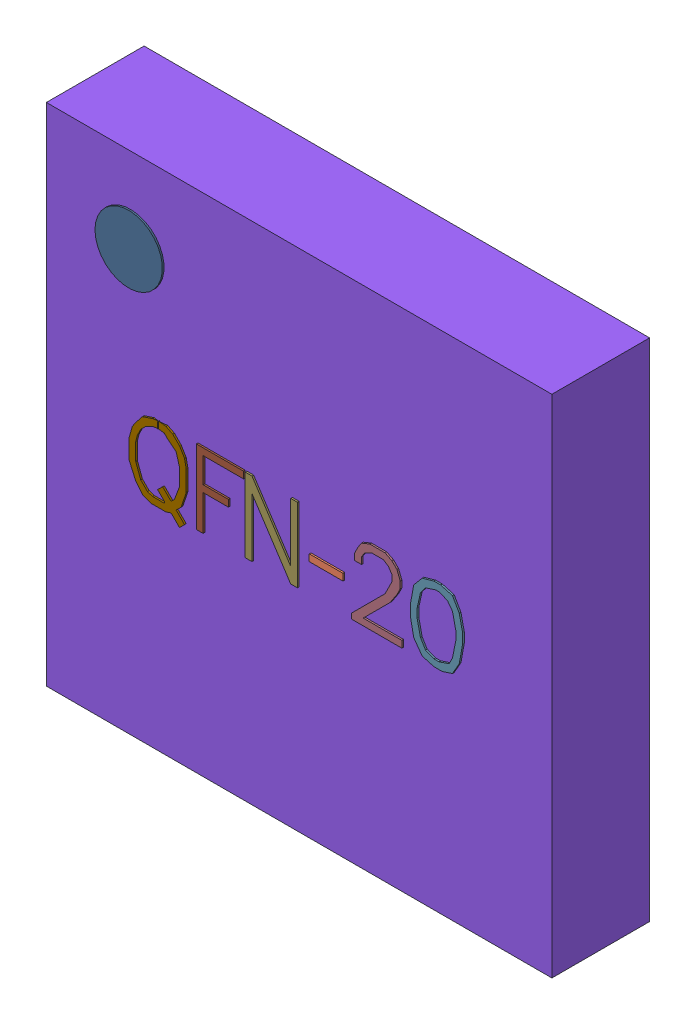
SolidWorks assembly User Library-QFN-20, configuration Default. Lengths in mm.
Overall size (3 3 0.73).
60 component instances, 15 part files, 0 mates.
Components (placement in the parent):
- User Library-QFN-20_Free-Models1-1: User Library-QFN-20_Free-Models1 [Default] at origin size (3 3 0.63)
  - User Library-QFN-20_479712337-1: User Library-QFN-20_479712337 [Default] at (0.045 -2.02 0.0127) size (0.35 0.3 0.02)
    - User Library-QFN-20_Extruded16-1: User Library-QFN-20_Extruded16 [Default] at origin size (0.35 0.3 0.02)
  - User Library-QFN-20_479712337-2: User Library-QFN-20_479712337 [Default] at (0.045 -1.52 0.0127) size (0.35 0.3 0.02)
    - User Library-QFN-20_Extruded16-1: User Library-QFN-20_Extruded16 [Default] at origin size (0.35 0.3 0.02)
  - User Library-QFN-20_479712337-3: User Library-QFN-20_479712337 [Default] at (0.045 -1.02 0.0127) size (0.35 0.3 0.02)
    - User Library-QFN-20_Extruded16-1: User Library-QFN-20_Extruded16 [Default] at origin size (0.35 0.3 0.02)
  - User Library-QFN-20_479711313-1: User Library-QFN-20_479711313 [Default] at (1.44 -1.32 0.6127) size (0.2 0.04 0.01)
    - User Library-QFN-20_Extruded23-1: User Library-QFN-20_Extruded23 [Default] at origin size (0.2 0.04 0.01)
  - User Library-QFN-20_479711441-1: User Library-QFN-20_479711441 [Default] at (0.005 -0.005 0.0127) size (0.43 0.43 0.02)
    - User Library-QFN-20_Extruded21-1: User Library-QFN-20_Extruded21 [Default] at origin size (0.43 0.43 0.02)
  - User Library-QFN-20_479711441-2: User Library-QFN-20_479711441 [Default] at (2.535 -0.005 0.0127) size (0.43 0.43 0.02)
    - User Library-QFN-20_Extruded21-1: User Library-QFN-20_Extruded21 [Default] at origin size (0.43 0.43 0.02)
  - User Library-QFN-20_479711441-3: User Library-QFN-20_479711441 [Default] at (2.535 -2.535 0.0127) size (0.43 0.43 0.02)
    - User Library-QFN-20_Extruded21-1: User Library-QFN-20_Extruded21 [Default] at origin size (0.43 0.43 0.02)
  - User Library-QFN-20_479712337-4: User Library-QFN-20_479712337 [Default] at (0.045 -0.52 0.0127) size (0.35 0.3 0.02)
    - User Library-QFN-20_Extruded16-1: User Library-QFN-20_Extruded16 [Default] at origin size (0.35 0.3 0.02)
  - User Library-QFN-20_479712209-1: User Library-QFN-20_479712209 [Default] at (2.02 -0.045 0.0127) size (0.3 0.35 0.02)
    - User Library-QFN-20_Extruded20-1: User Library-QFN-20_Extruded20 [Default] at origin size (0.3 0.35 0.02)
  - User Library-QFN-20_479706833-1: User Library-QFN-20_479706833 [Default] at (2.495 -2.02 0.0127) size (0.35 0.3 0.02)
    - User Library-QFN-20_Extruded19-1: User Library-QFN-20_Extruded19 [Default] at origin size (0.35 0.3 0.02)
  - User Library-QFN-20_479706577-1: User Library-QFN-20_479706577 [Default] at (0.52 -2.495 0.0127) size (0.3 0.35 0.02)
    - User Library-QFN-20_Extruded22-1: User Library-QFN-20_Extruded22 [Default] at origin size (0.3 0.35 0.02)
  - User Library-QFN-20_479711441-4: User Library-QFN-20_479711441 [Default] at (0.005 -2.535 0.0127) size (0.43 0.43 0.02)
    - User Library-QFN-20_Extruded21-1: User Library-QFN-20_Extruded21 [Default] at origin size (0.43 0.43 0.02)
  - User Library-QFN-20_479706577-2: User Library-QFN-20_479706577 [Default] at (2.02 -2.495 0.0127) size (0.3 0.35 0.02)
    - User Library-QFN-20_Extruded22-1: User Library-QFN-20_Extruded22 [Default] at origin size (0.3 0.35 0.02)
  - User Library-QFN-20_479706577-3: User Library-QFN-20_479706577 [Default] at (1.52 -2.495 0.0127) size (0.3 0.35 0.02)
    - User Library-QFN-20_Extruded22-1: User Library-QFN-20_Extruded22 [Default] at origin size (0.3 0.35 0.02)
  - User Library-QFN-20_479706577-4: User Library-QFN-20_479706577 [Default] at (1.02 -2.495 0.0127) size (0.3 0.35 0.02)
    - User Library-QFN-20_Extruded22-1: User Library-QFN-20_Extruded22 [Default] at origin size (0.3 0.35 0.02)
  - User Library-QFN-20_479706833-2: User Library-QFN-20_479706833 [Default] at (2.495 -0.52 0.0127) size (0.35 0.3 0.02)
    - User Library-QFN-20_Extruded19-1: User Library-QFN-20_Extruded19 [Default] at origin size (0.35 0.3 0.02)
  - User Library-QFN-20_479706833-3: User Library-QFN-20_479706833 [Default] at (2.495 -1.02 0.0127) size (0.35 0.3 0.02)
    - User Library-QFN-20_Extruded19-1: User Library-QFN-20_Extruded19 [Default] at origin size (0.35 0.3 0.02)
  - User Library-QFN-20_479706833-4: User Library-QFN-20_479706833 [Default] at (2.495 -1.52 0.0127) size (0.35 0.3 0.02)
    - User Library-QFN-20_Extruded19-1: User Library-QFN-20_Extruded19 [Default] at origin size (0.35 0.3 0.02)
  - User Library-QFN-20_479712209-2: User Library-QFN-20_479712209 [Default] at (0.52 -0.045 0.0127) size (0.3 0.35 0.02)
    - User Library-QFN-20_Extruded20-1: User Library-QFN-20_Extruded20 [Default] at origin size (0.3 0.35 0.02)
  - User Library-QFN-20_479712209-3: User Library-QFN-20_479712209 [Default] at (1.02 -0.045 0.0127) size (0.3 0.35 0.02)
    - User Library-QFN-20_Extruded20-1: User Library-QFN-20_Extruded20 [Default] at origin size (0.3 0.35 0.02)
  - User Library-QFN-20_479712209-4: User Library-QFN-20_479712209 [Default] at (1.52 -0.045 0.0127) size (0.3 0.35 0.02)
    - User Library-QFN-20_Extruded20-1: User Library-QFN-20_Extruded20 [Default] at origin size (0.3 0.35 0.02)
  - User Library-QFN-20_479707217-1: User Library-QFN-20_479707217 [Default] at (1.27 -1.27 0.0127) size (1.7 1.7 0.02)
    - User Library-QFN-20_Extruded14-1: User Library-QFN-20_Extruded14 [Default] at origin size (1.7 1.7 0.02)
  - User Library-QFN-20_479706449-1: User Library-QFN-20_479706449 [Default] at (1.27 -1.27 0.0327) size (3 3 0.58)
    - User Library-QFN-20_Extruded15-1: User Library-QFN-20_Extruded15 [Default] at origin size (3 3 0.58)
  - User Library-QFN-20_479710545-1: User Library-QFN-20_479710545 [Default] at (0.44 -1.31 0.6127) size (0.34 0.51 0.05)
    - User Library-QFN-20_Extruded25-1: User Library-QFN-20_Extruded25 [Default] at origin size (0.34 0.51 0.05)
  - User Library-QFN-20_479480465-1: User Library-QFN-20_479480465 [Default] at (0.2684 -0.2696 0.6127) size (0.4 0.4 0.01)
    - User Library-QFN-20_Cylinder1-1: User Library-QFN-20_Cylinder1 [Default] at origin size (0.4 0.4 0.01)
  - User Library-QFN-20_479711953-1: User Library-QFN-20_479711953 [Default] at (0.81 -1.29 0.6127) size (0.28 0.44 0.01)
    - User Library-QFN-20_Extruded13-1: User Library-QFN-20_Extruded13 [Default] at origin size (0.28 0.44 0.01)
  - User Library-QFN-20_479709777-1: User Library-QFN-20_479709777 [Default] at (1.115 -1.29 0.6127) size (0.31 0.44 0.01)
    - User Library-QFN-20_Extruded18-1: User Library-QFN-20_Extruded18 [Default] at origin size (0.31 0.44 0.01)
  - User Library-QFN-20_479710033-1: User Library-QFN-20_479710033 [Default] at (1.74 -1.29 0.6127) size (0.3 0.44 0.01)
    - User Library-QFN-20_Extruded24-1: User Library-QFN-20_Extruded24 [Default] at origin size (0.3 0.44 0.01)
  - User Library-QFN-20_479710801-1: User Library-QFN-20_479710801 [Default] at (2.095 -1.29 0.6127) size (0.31 0.44 0.01)
    - User Library-QFN-20_Extruded17-1: User Library-QFN-20_Extruded17 [Default] at origin size (0.31 0.44 0.01)
- User Library-QFN-20_Board1-1: User Library-QFN-20_Board1 [Default] at (0 0 -0.0838) size (0.01 0.01 0.1)
